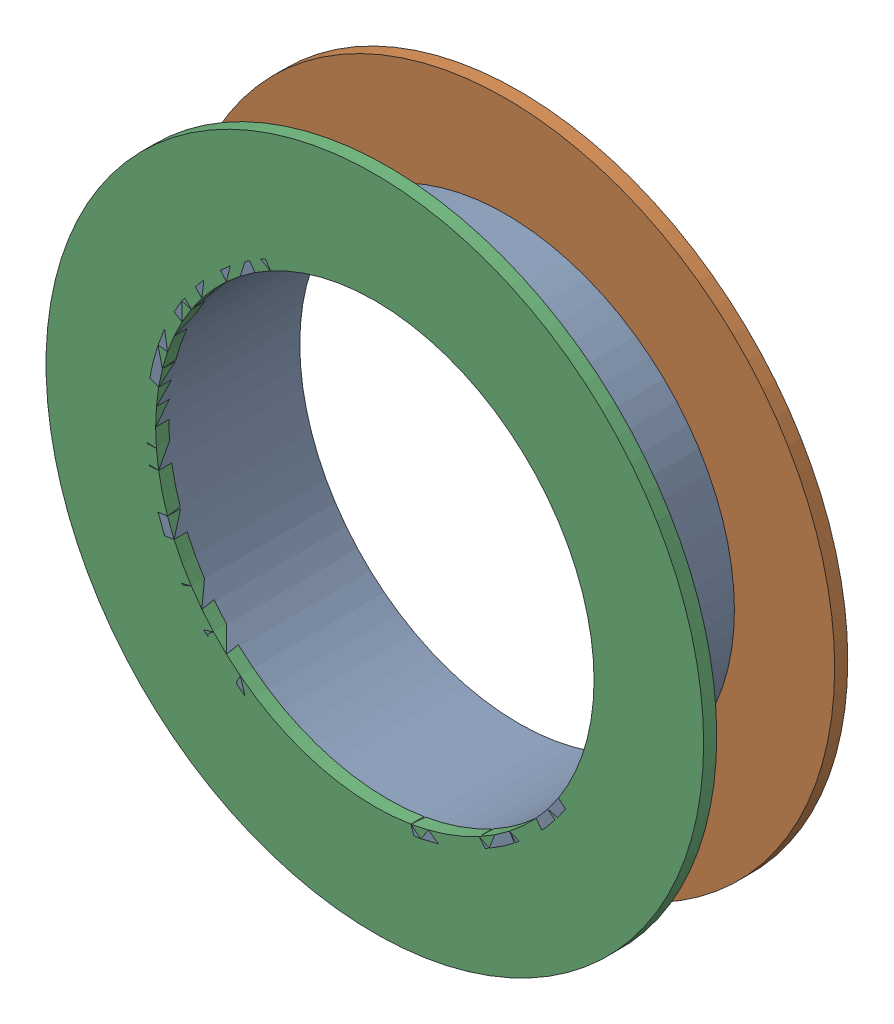
SolidWorks assembly Pad U1-4(13.758mm,4.578mm) on Multi-Layer, configuration Predeterminado. Lengths in mm.
Overall size (1.79 1.79 0.39).
6 component instances, 2 part files, 0 mates.
Components (placement in the parent):
- Pad Hole-1: Pad Hole [Predeterminado] at (13.7584 4.5777 -0.4013) size (1.24 1.24 0.39)
  - Pad Hole-Part-1-1: Pad Hole-Part-1 [Predeterminado] at origin size (1.24 1.24 0.39)
- Top Layer-1: Top Layer [Predeterminado] at (13.7584 4.5777 -0.4013) size (1.79 1.79 0.04)
  - Top Layer-Part-1-1: Top Layer-Part-1 [Predeterminado] at origin size (1.79 1.79 0.04)
- Top Layer-2: Top Layer [Predeterminado] at (13.7584 4.5777 -0.0457) size (1.79 1.79 0.04)
  - Top Layer-Part-1-1: Top Layer-Part-1 [Predeterminado] at origin size (1.79 1.79 0.04)
